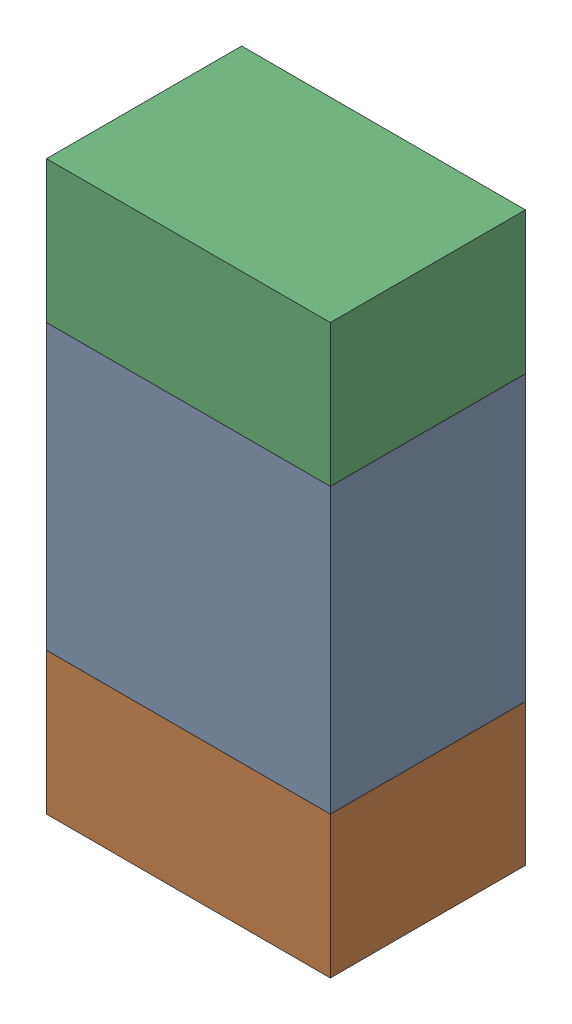
SolidWorks assembly R14, configuration ﾃﾞﾌｫﾙﾄ. Lengths in mm.
Overall size (0.8 1.6 0.55).
6 component instances, 2 part files, 0 mates.
Components (placement in the parent):
- 689261648-1: 689261648 [ﾃﾞﾌｫﾙﾄ] at (73.5001 48.25 0) size (0.8 0.8 0.55)
  - Extruded_33-1: Extruded_33 [ﾃﾞﾌｫﾙﾄ] at origin size (0.8 0.8 0.55)
- 689261784-1: 689261784 [ﾃﾞﾌｫﾙﾄ] at (73.5001 47.6499 0) size (0.8 0.4 0.55)
  - Extruded_34-1: Extruded_34 [ﾃﾞﾌｫﾙﾄ] at origin size (0.8 0.4 0.55)
- 689261784-2: 689261784 [ﾃﾞﾌｫﾙﾄ] at (73.5001 48.8499 0) size (0.8 0.4 0.55)
  - Extruded_34-1: Extruded_34 [ﾃﾞﾌｫﾙﾄ] at origin size (0.8 0.4 0.55)
